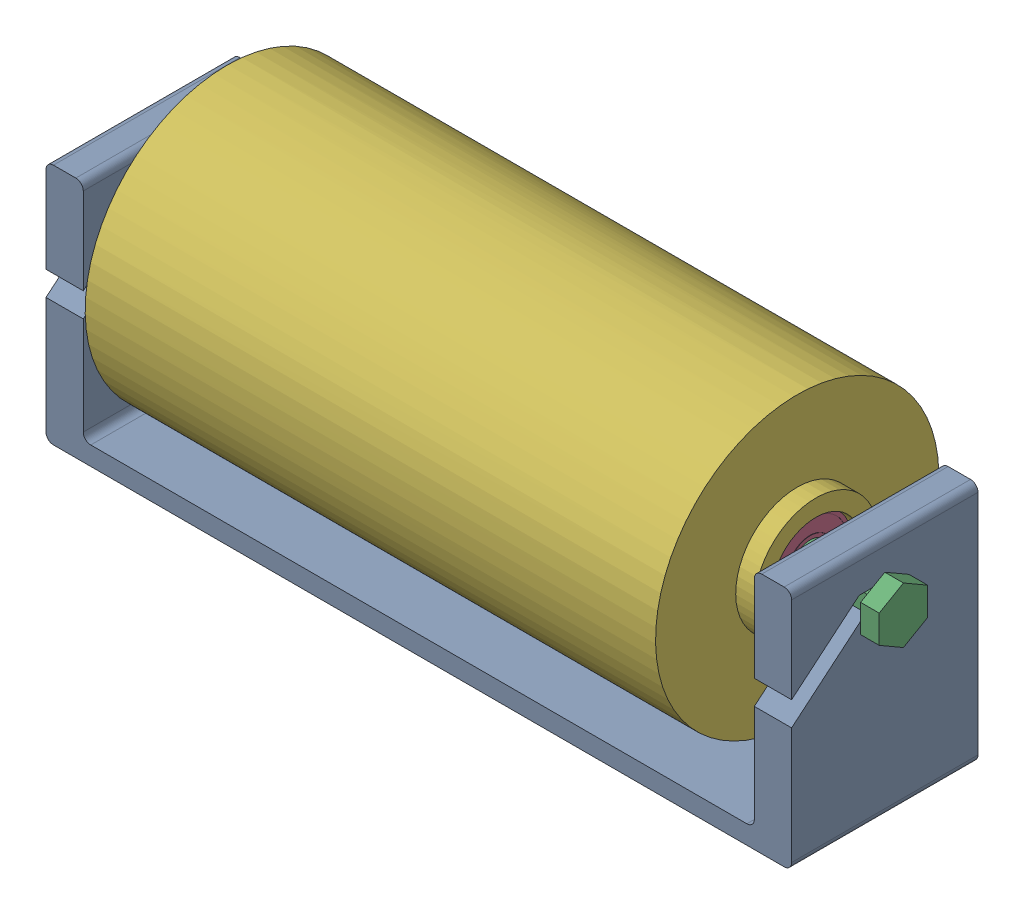
SolidWorks assembly LightningRocket_StringSpoolAssembly, configuration Default. Lengths in mm.
Overall size (210 96.41 95.95).
6 component instances, 5 part files, 13 mates.
Components (placement in the parent):
- LightningRocket_Base_Mk2-1: LightningRocket_Base_Mk2 [Default] at origin size (200 65 50)
- LightningRocket_Axle_String-1: LightningRocket_Axle_String [Default] at (-100 49.4358 0) x (0 0 -1) z (0 -1 0) size (12.99 109 15)
- LightningRocket_Axle_String-Pair-1: LightningRocket_Axle_String-Pair [Default] at (100 49.4358 0) x (0 0 1) z (0 -1 0) size (12.99 105 15)
- Bearing-1: Bearing [Default] at (76.5 49.4358 0) x (0 -1 0) z (0 0 1) size (22 7 22)
- Bearing-2: Bearing [Default] at (-76.5 49.4358 0) x (0 1 0) z (0 0 1) size (22 7 22)
- StringSpool-1: StringSpool [Default] at (0 48.4359 -0.0083) x (1 0 0) z (0 -0.312568 0.949895) size (163 76 76)
Mates (geometry in assembly coordinates):
- Coincident1: coordinate: point of LightningRocket_Base_Mk2-1
- Coincident2: coincident anti-aligned: plane of LightningRocket_Base_Mk2-1 through (100 46.9358 -2.5) normal (0 1 0); plane of LightningRocket_Axle_String-1 through (-90 46.9358 -2.5) normal (0 -1 0)
- Coincident3: coincident anti-aligned: plane of LightningRocket_Base_Mk2-1 through (-100 5 25) normal (-1 0 0); plane of LightningRocket_Axle_String-1 through (-100 49.4358 0) normal (1 0 0)
- Coincident4: coincident anti-aligned: plane of LightningRocket_Base_Mk2-1 through (100 55 -2.5) normal (0 0 1); plane of LightningRocket_Axle_String-1 through (-90 46.9358 -2.5) normal (0 0 -1)
- Coincident5: coincident anti-aligned: plane of LightningRocket_Base_Mk2-1 through (-100 46.9358 -2.5) normal (0 1 0); plane of LightningRocket_Axle_String-Pair-1 through (90 46.9358 2.5) normal (0 -1 0)
- Coincident6: coincident anti-aligned: plane of LightningRocket_Base_Mk2-1 through (100 5 25) normal (1 0 0); plane of LightningRocket_Axle_String-Pair-1 through (100 49.4358 0) normal (-1 0 0)
- Concentric1: concentric anti-aligned: cylinder of LightningRocket_Axle_String-1 through (101.3137 49.4358 0) axis (-1 0 0) radius 4; cylinder of LightningRocket_Axle_String-Pair-1 through (-101.3137 49.4358 0) axis (1 0 0) radius 4
- Concentric2: concentric anti-aligned: cylinder of LightningRocket_Axle_String-Pair-1 through (-101.3137 49.4358 0) axis (1 0 0) radius 4; cylinder of Bearing-1 through (80 49.4358 0) axis (-1 0 0) radius 4
- Coincident7: coincident anti-aligned: plane of LightningRocket_Axle_String-Pair-1 through (80 49.4358 0) normal (-1 0 0); plane of Bearing-1 through (80 49.4358 0) normal (1 0 0)
- Concentric3: concentric anti-aligned: cylinder of LightningRocket_Axle_String-1 through (101.3137 49.4358 0) axis (-1 0 0) radius 4; cylinder of Bearing-2 through (-80 49.4358 0) axis (1 0 0) radius 4
- Coincident8: coincident anti-aligned: plane of LightningRocket_Axle_String-1 through (-80 49.4358 0) normal (1 0 0); plane of Bearing-2 through (-80 49.4358 0) normal (-1 0 0)
- Width1: width aligned: plane of StringSpool-1 through (81.5 48.4359 -0.0083) normal (1 0 0); plane of StringSpool-1 through (-81.5 48.4359 -0.0083) normal (-1 0 0); plane of Bearing-1 through (79.9 49.4358 0) normal (1 0 0); plane of Bearing-2 through (-79.9 49.4358 0) normal (-1 0 0)
- Tangent1: tangent: circle of Bearing-1; cylinder of StringSpool-1 through (81.5 48.4359 -0.0083) axis (-1 0 0) radius 12
